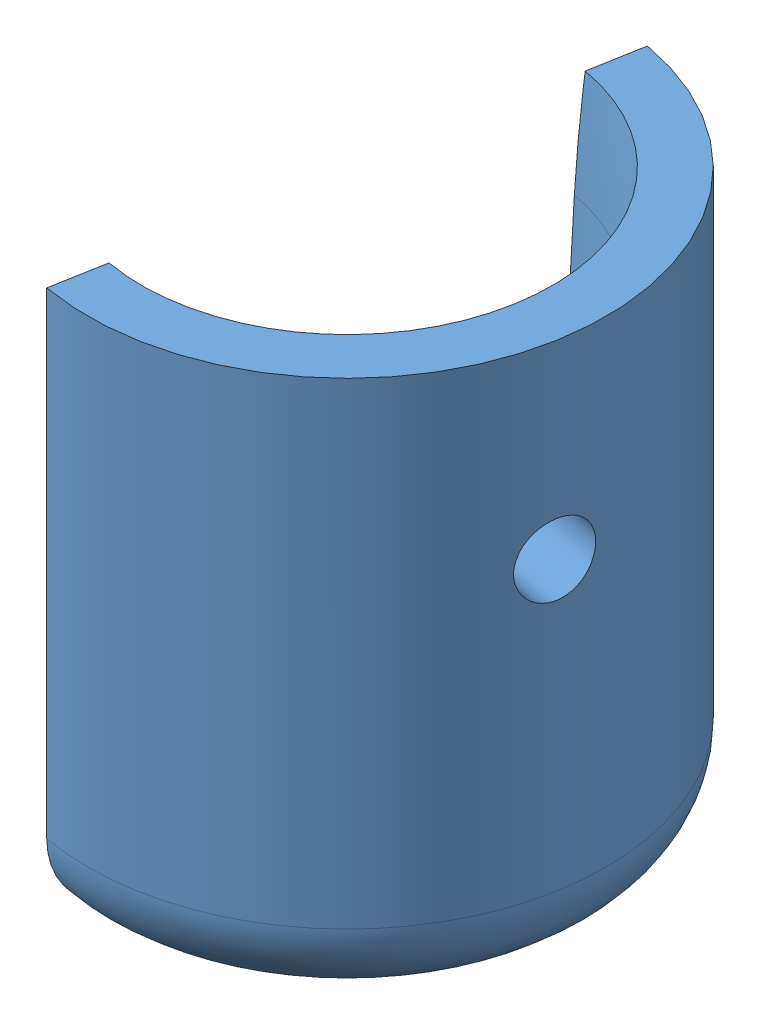
SolidWorks assembly Sleeve-old, configuration Default. Lengths in mm.
Overall size (34.47 89.02 60.83).
2 component instances, 2 part files, 2 mates.
Components (placement in the parent):
- Tibial End - Copy-2: Tibial End - Copy [Default] at (77.0383 -24.6389 116.5485) size (46.69 144.7 53.03) (hidden)
- Sleeve-2: Sleeve [Default] at (77.0383 -24.789 116.5485) x (0.984502 0 0.175374) z (-0.175374 0 0.984502) size (26.42 52.07 48.26)
Mates (geometry in assembly coordinates):
- Parallel1: parallel: cone of Tibial End - Copy-2 through (77.0383 -24.6389 116.5485) axis (0 -1 0); cylinder of Sleeve-2 through (77.0383 -26.059 116.5485) axis (0 -1 0) radius 24.13
- Concentric1: concentric: cone of Tibial End - Copy-2 through (77.0383 -24.6389 116.5485) axis (0 -1 0); cylinder of Sleeve-2 through (77.0383 -26.059 116.5485) axis (0 -1 0) radius 24.13
